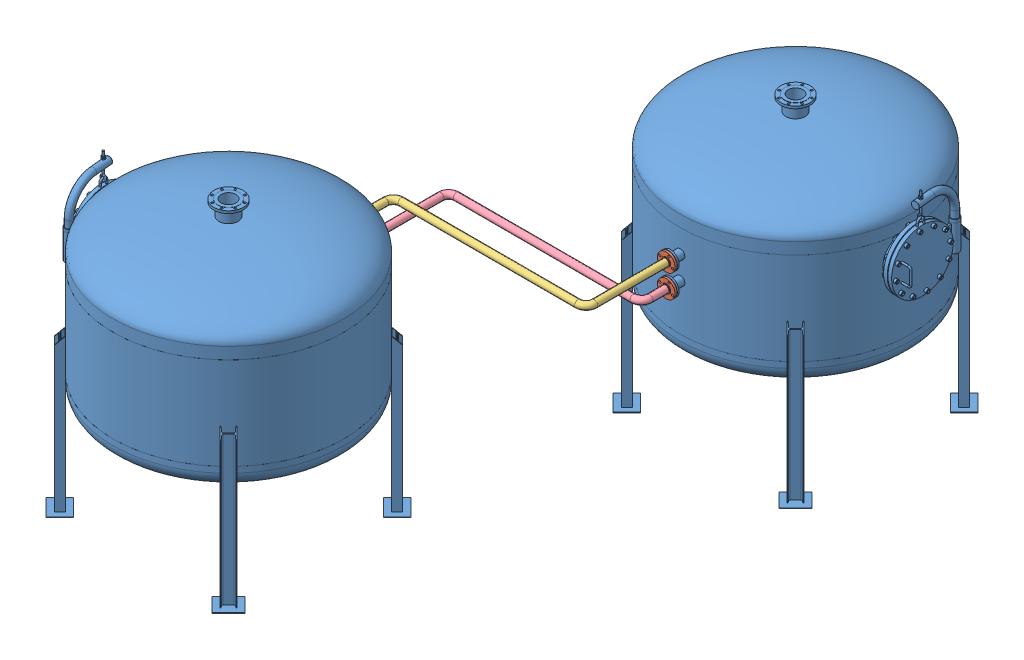
SolidWorks assembly Ensamblaje3, configuration Predeterminado. Lengths in mm.
Overall size (4038.85 2499.06 5243.14).
10 component instances, 4 part files, 1 mates.
Components (placement in the parent):
- sample-tank-07-1: sample-tank-07 [Default] at (-381.7926 978.2012 33.1928) size (2184.14 2332.61 2111.59)
- sample-tank-07-2: sample-tank-07 [Default] at (-2052.3636 978.2012 3276.3329) x (-1 0 0) z (0 0 -1) size (2184.14 2332.61 2111.59)
- Pipe_2-Ensamblaje3-1: Pipe_2-Ensamblaje3 [Predeterminado] at origin size (1846.35 1756.06 1039.99)
  - slip on weld flange-1: slip on weld flange [Slip On Flange 150-NPS2] at (-381.7926 678.2012 1134.7803) x (0.923728 0.383049 0) z (0 0 -1) size (152.4 152.4 25.41)
  - slip on weld flange-2: slip on weld flange [Slip On Flange 150-NPS2] at (-2052.3636 678.2012 2174.7454) size (152.4 152.4 25.41)
  - 2inSchedule40^Pipe_2-Ensamblaje3-1: 2inSchedule40^Pipe_2-Ensamblaje3 [Pipe 2 in, Sch 40] at (-381.7926 678.2012 1141.1303) x (0.707107 0.707107 0) z (0 0 1) size (1241.72 1241.72 1027.27) (virtual)
- Pipe_3-Ensamblaje3-1: Pipe_3-Ensamblaje3 [Predeterminado] at origin size (1846.35 1756.06 1039.99)
  - slip on weld flange-1: slip on weld flange [Slip On Flange 150-NPS2] at (-2052.3636 478.2012 2174.7454) size (152.4 152.4 25.41)
  - slip on weld flange-2: slip on weld flange [Slip On Flange 150-NPS2] at (-381.7926 478.2012 1134.7803) x (0.923728 0.383049 0) z (0 0 -1) size (152.4 152.4 25.41)
  - 2inSchedule40^Pipe_3-Ensamblaje3-1: 2inSchedule40^Pipe_3-Ensamblaje3 [Pipe 2 in, Sch 40] at (-2052.3636 478.2012 2168.3954) x (0.707107 0.707107 0) z (0 0 -1) size (1241.72 1241.72 1027.27) (virtual)
Mates (geometry in assembly coordinates):
- Coincidente2: coincident: plane of assembly; plane of assembly; plane of sample-tank-07-1 through (217.5511 -942.8255 776.2206) normal (0 -1 0); plane of sample-tank-07-2 through (-1309.3358 -942.8255 2676.9891) normal (0 -1 0)
